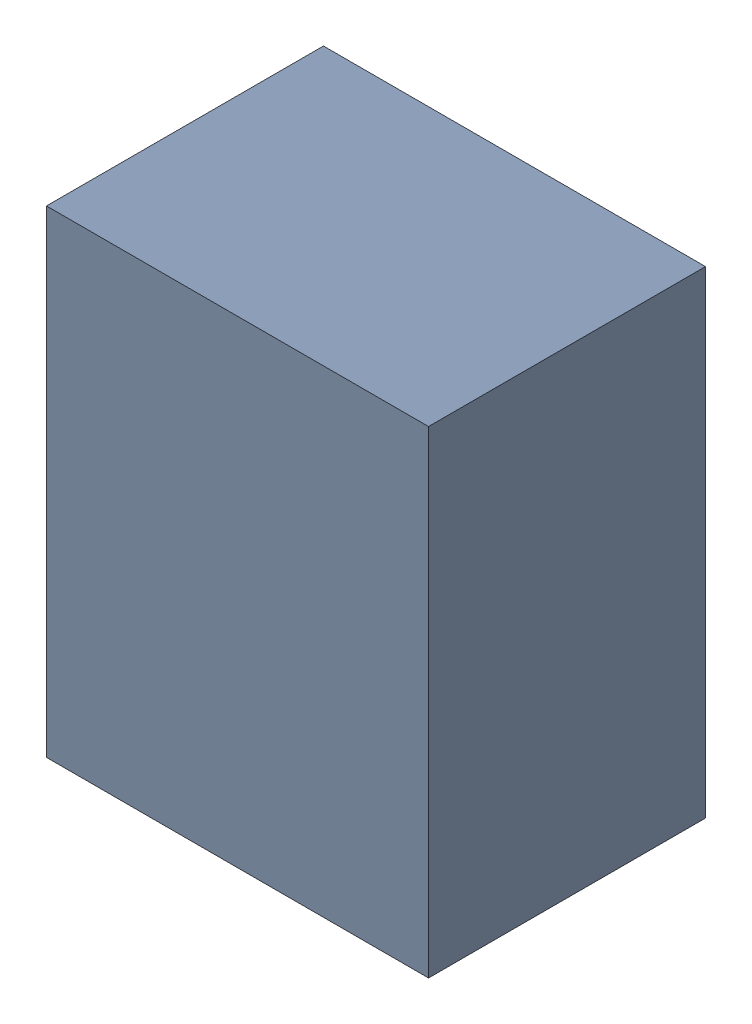
SolidWorks assembly U28, configuration Default. Lengths in mm.
Overall size (0.8 1 0.58).
2 component instances, 1 part files, 0 mates.
Components (placement in the parent):
- 836751984-1: 836751984 [Default] at (133.05 70.65 0.5) size (0.8 1 0.58)
  - Extruded_32-1: Extruded_32 [Default] at origin size (0.8 1 0.58)
